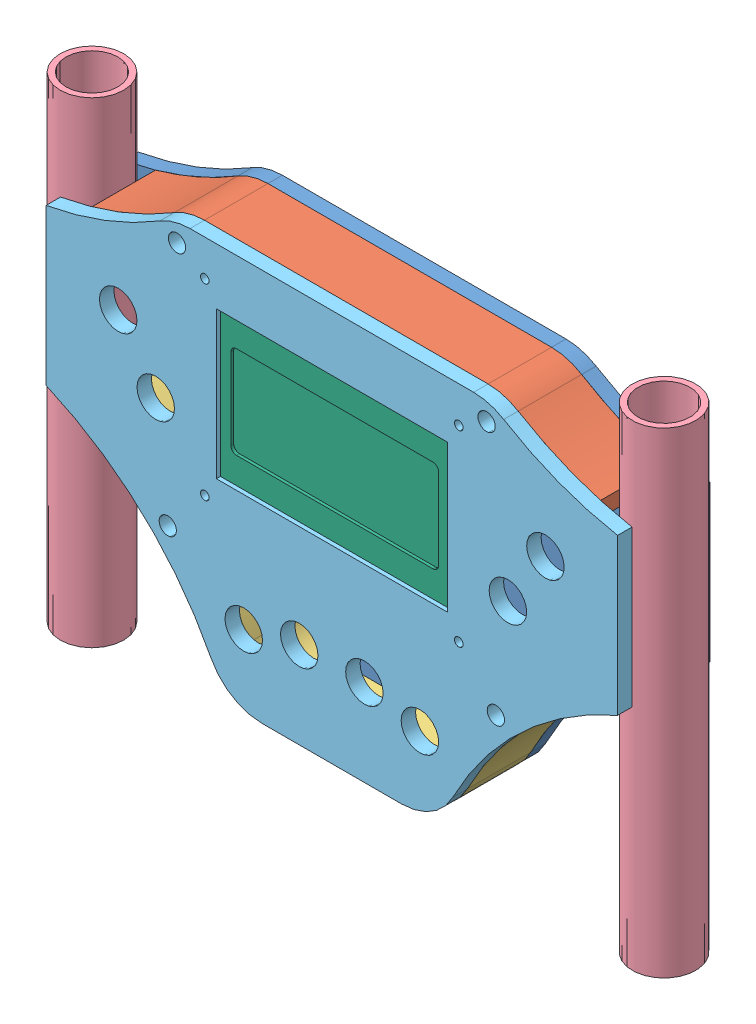
SolidWorks assembly volante_montagem, configuration Valor predeterminado. Lengths in mm.
Overall size (224.51 165 32).
8 component instances, 7 part files, 17 mates.
Components (placement in the parent):
- volante_costas-2: volante_costas [Valor predeterminado] at (161.8317 118.4647 60.1504) size (198 136 5)
- volante_parede_superior-2: volante_parede_superior [Valor predeterminado] at (161.8317 118.4647 65.1504) size (176.19 20.68 22)
- volante_parede_inferior-1: volante_parede_inferior [Valor predeterminado] at (161.8317 118.4647 65.1504) size (176.26 64.29 22)
- volante_tubo-4: volante_tubo [Valor predeterminado] at (62.7372 35.4647 76.15) size (22 165 22)
- volante_tubo-5: volante_tubo [Valor predeterminado] at (260.9262 35.4647 76.15) x (-0.819926 0 0.572469) z (-0.572469 0 -0.819926) size (22 165 22)
- volante_frente-2: volante_frente [Valor predeterminado] at (161.8317 118.4647 87.1504) size (198 136 5)
- Peça1^volante_montagem-1: Peça1^volante_montagem [Valor predeterminado] at origin (virtual)
- display_128x64-1: display_128x64 [Valor predeterminado] at (161.8317 141.4647 82.1504) size (93 70 10.6)
Mates (geometry in assembly coordinates):
- Coincidente2: coincident aligned: plane of volante_costas-2 through (112.7125 186.4647 65.1504) normal (0 1 0); plane of volante_parede_superior-2 through (112.7125 186.4647 87.1504) normal (0 1 0)
- Distância1: distance = 0 mm: line of volante_parede_superior-2 through (210.9508 186.4647 87.1504) axis (0 0 -1); line of volante_costas-2 through (210.9508 186.4647 65.1504) axis (0 0 -1)
- Distância2: distance = 0 mm: line of volante_parede_superior-2 through (210.9508 186.4647 65.1504) axis (-1 0 0); line of volante_costas-2 through (210.9508 186.4647 65.1504) axis (-1 0 0)
- Coincidente3: coincident aligned: plane of volante_costas-2 through (137.7254 50.4647 65.1504) normal (0 -1 0); plane of volante_parede_inferior-1 through (137.7254 50.4647 87.1504) normal (0 -1 0)
- Distância3: distance = 0 mm: line of volante_parede_inferior-1 through (137.7254 50.4647 65.1504) axis (1 0 0); line of volante_costas-2 through (137.7254 50.4647 65.1504) axis (1 0 0)
- Distância4: distance = 0 mm: line of volante_parede_inferior-1 through (185.9379 50.4647 87.1504) axis (0 0 -1); line of volante_costas-2 through (185.9379 50.4647 65.1504) axis (0 0 -1)
- Coincidente4: coincident: line of volante_costas-2 through (260.8317 114.4647 65.1504) axis (0 1 0); cylinder of volante_tubo-5 through (260.9262 200.4647 76.15) axis (0 -1 0) radius 11
- Tangente1: tangent anti-aligned: plane of volante_parede_superior-2 through (249.9262 165.7866 87.1504) normal (1 0 0); cylinder of volante_tubo-5 through (260.9262 200.4647 76.15) axis (0 -1 0) radius 11
- Distância5: distance = 14 mm aligned: plane of volante_tubo-5 through (260.9262 200.4647 76.15) normal (0 1 0); plane of volante_parede_superior-2 through (112.7125 186.4647 87.1504) normal (0 1 0)
- Coincidente5: coincident: line of volante_costas-2 through (62.8317 168.4647 65.1504) axis (0 -1 0); cylinder of volante_tubo-4 through (62.7372 200.4647 76.15) axis (0 -1 0) radius 11
- Tangente2: tangent anti-aligned: plane of volante_parede_superior-2 through (73.7372 165.7866 87.1504) normal (-1 0 0); cylinder of volante_tubo-4 through (62.7372 200.4647 76.15) axis (0 -1 0) radius 11
- Distância6: distance = 14 mm aligned: plane of volante_tubo-4 through (62.7372 200.4647 76.15) normal (0 1 0); plane of volante_parede_superior-2 through (112.7125 186.4647 87.1504) normal (0 1 0)
- Concêntrico1: concentric anti-aligned: cylinder of volante_frente-2 through (205.8317 173.9647 92.1504) axis (0 0 -1) radius 1.5; cylinder of display_128x64-1 through (205.8317 173.9647 80.5504) axis (0 0 1) radius 1.25
- Concêntrico2: concentric aligned: circle of volante_frente-2; circle of display_128x64-1
- Coincidente6: coincident anti-aligned: plane of volante_frente-2 through (281.4342 281.6042 87.1504) normal (0 0 -1); plane of display_128x64-1 through (161.8317 141.4647 87.1504) normal (0 0 1)
- Concêntrico4: concentric aligned: cylinder of volante_parede_inferior-1 through (218.6666 93.4359 87.1504) axis (0 0 -1) radius 3; cylinder of volante_frente-2 through (218.6666 93.4359 92.1504) axis (0 0 -1) radius 3
- Coincidente7: coincident anti-aligned: plane of volante_parede_inferior-1 through (17.5533 8.6973 87.1504) normal (0 0 1); plane of volante_frente-2 through (281.4342 281.6042 87.1504) normal (0 0 -1)
